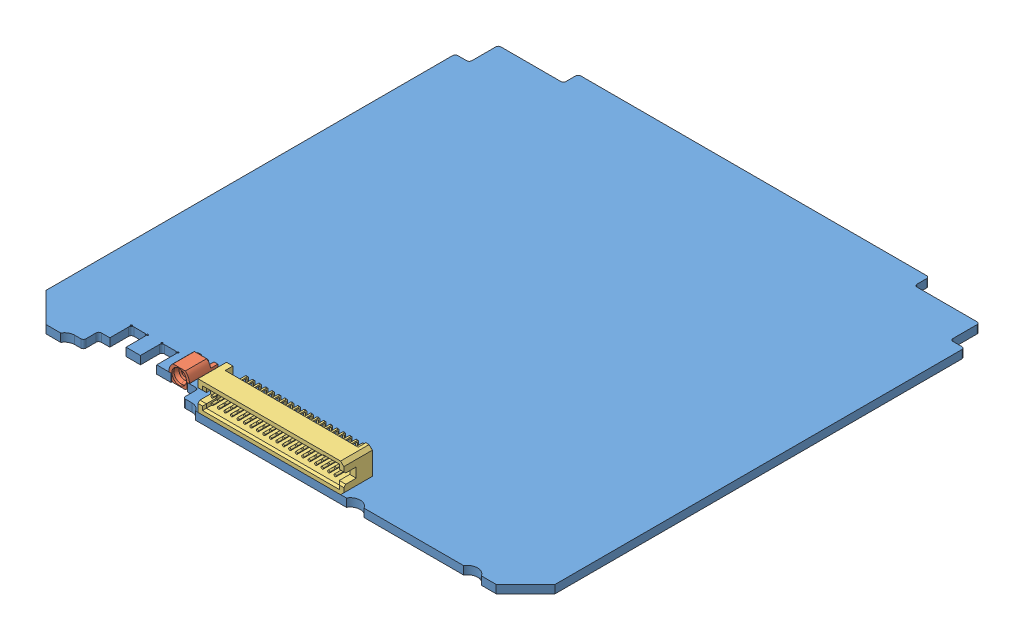
SolidWorks assembly GPSCard, configuration Default. Lengths in mm.
Overall size (99.8 7.62 107.17).
3 component instances, 3 part files, 9 mates.
Components (placement in the parent):
- GenericCardPCBDefinition-1: GenericCardPCBDefinition [RF] at origin size (99.8 1.6 107.17)
- Molex, LLC 0733000020 (Card Connector)-1: Molex, LLC 0733000020 (Card Connector) [Default] at (-22 0.9778 40.8) size (3.99 3.17 5.61)
- TFM_120_01_L_D_RA_defeature-1: TFM_120_01_L_D_RA_defeature [Default] at (0 3.6575 39.237) x (1 0 0) z (0 -1 0) size (28.58 7.49 7.62)
Mates (geometry in assembly coordinates):
- Coincident1: coincident anti-aligned: plane of Molex, LLC 0733000020 (Card Connector)-1 through (-20.0061 0.8 40.8) normal (0 -1 0); plane of GenericCardPCBDefinition-1 through (0 0.8 0) normal (0 1 0)
- Coincident2: coincident aligned: plane of GenericCardPCBDefinition-1 through (0 -0.8 40.8) normal (0 0 1); plane of Molex, LLC 0733000020 (Card Connector)-1 through (-22 -0.6097 40.8) normal (0 0 1)
- Symmetric1: symmetric aligned: plane of GenericCardPCBDefinition-1 through (-23.59 -0.8 0) normal (1 0 0); plane of GenericCardPCBDefinition-1 through (-20.41 -0.8 0) normal (-1 0 0); plane of Molex, LLC 0733000020 (Card Connector)-1 through (-22 0.9778 40.8) normal (1 0 0)
- Coincident7: coincident: line of GenericCardPCBDefinition-1 through (0 0.8 -5.2282) axis (0 0 1); plane of TFM_120_01_L_D_RA_defeature-1 through (0 3.6575 39.237) normal (1 0 0)
- Coincident8: coincident anti-aligned: plane of GenericCardPCBDefinition-1 through (0 0.8 0) normal (0 1 0); plane of TFM_120_01_L_D_RA_defeature-1 through (-14.2875 0.8 44.825) normal (0 -1 0)
- Coincident9: coincident: line of GenericCardPCBDefinition-1 through (49.9 0.8 37.332) axis (-1 0 0); plane of TFM_120_01_L_D_RA_defeature-1 through (0 3.6575 37.332) normal (0 0 -1)
- Coincident10: coincident aligned: plane of GenericCardPCBDefinition-1 through (0 0 0) normal (0 0 1)
- Coincident11: coincident aligned: plane of GenericCardPCBDefinition-1 through (0 0 0) normal (0 1 0)
- Coincident12: coincident aligned: plane of GenericCardPCBDefinition-1 through (0 0 0) normal (1 0 0)
